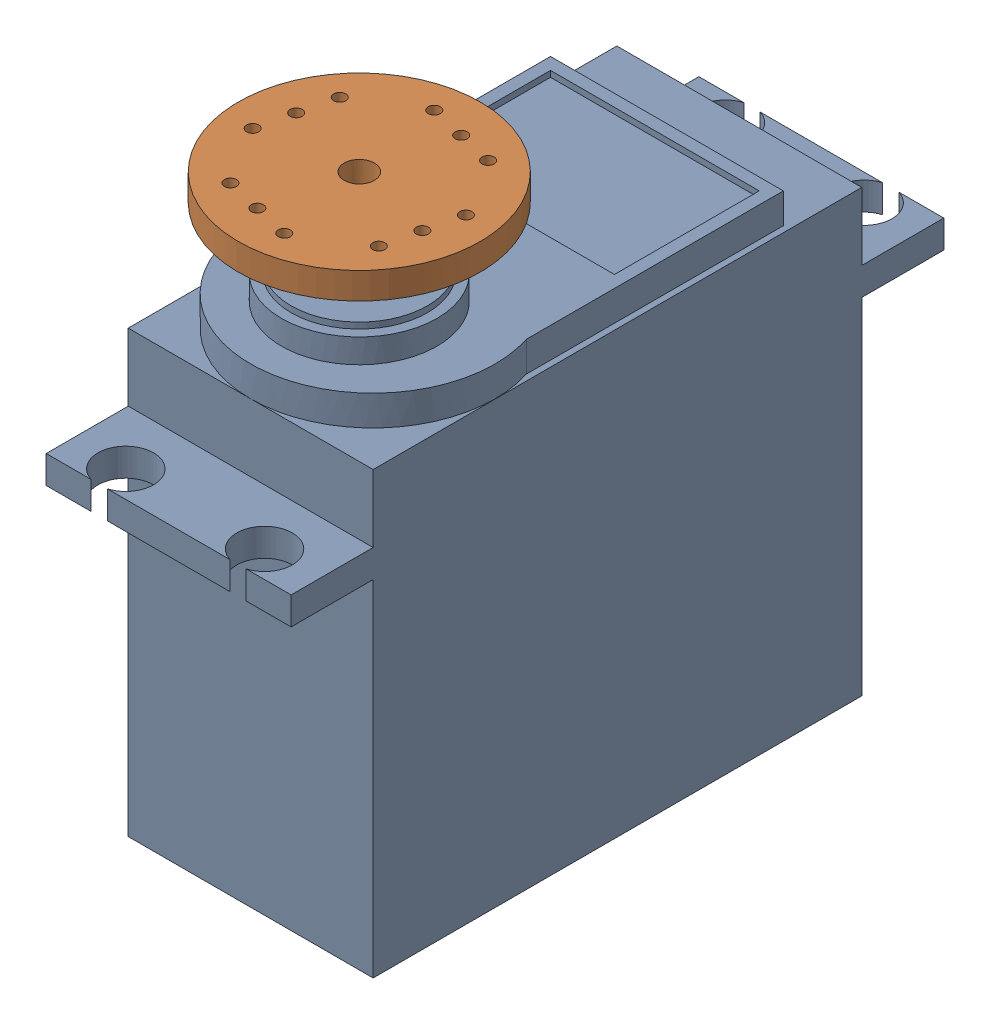
SolidWorks assembly MG996R-Servo-with-Hub, configuration Default. Lengths in mm.
Overall size (24.11 48.3 54.1).
2 component instances, 2 part files, 2 mates.
Components (placement in the parent):
- MG996R-Servo-1: MG996R-Servo [Default] at (29.3026 10.0421 49.0781) size (20.3 45.5 54.1)
- Servo-Hub-1: Servo-Hub [Default] at (29.3026 56.1421 60.3281) x (0.973354 0 0.229307) z (-0.229307 0 0.973354) size (20.05 5.6 20.05)
Mates (geometry in assembly coordinates):
- Concentric1: concentric aligned: cylinder of MG996R-Servo-1 through (29.3026 55.5421 60.3281) axis (0 -1 0) radius 3; cylinder of ServoAttachment-1 through (29.3026 55.5421 60.3281) axis (0 -1 0) radius 3
- Coincident1: coincident anti-aligned: plane of MG996R-Servo-1 through (29.3026 55.5421 60.3281) normal (0 1 0); plane of ServoAttachment-1 through (29.3026 55.5421 60.3281) normal (0 -1 0)
